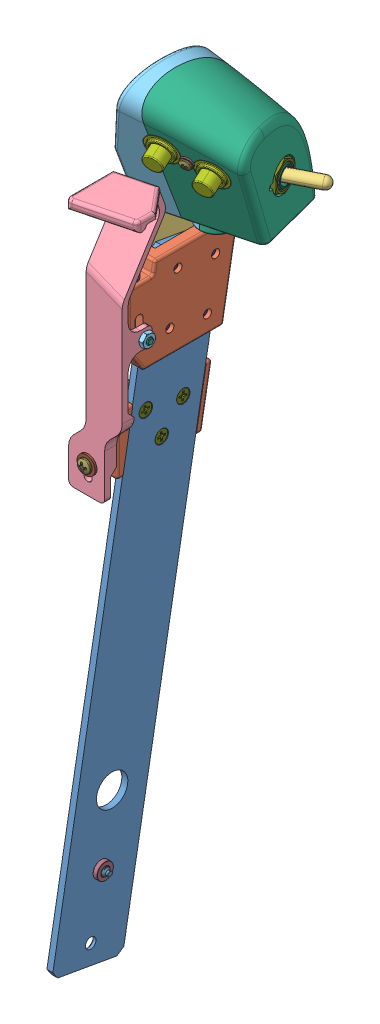
SolidWorks assembly Outboard Throttle Arm, configuration Default. Lengths in mm.
Overall size (82.55 408.55 128.06).
56 component instances, 35 part files, 59 mates.
Components (placement in the parent):
- Throttle Arm LH-1: Throttle Arm LH [Default] at (7.9447 45.466 -95.9039) x (0 0.984808 -0.173648) z (-1 0 0) size (312.92 38.1 3.17)
- LH Upper Adapter-1: LH Upper Adapter [Default] at (46.6096 413.27 112.6698) x (1 0 0) z (0 0.866025 -0.5) size (19.05 83.25 111.93)
- LH Grip Adapter-1: LH Grip Adapter [Default] at (1.3214 0.096 -0.0398) size (3.17 100.05 48.62)
- LH Finger Lift2-1: LH Finger Lift2 [Default] at (35.8375 39.1173 -95.0721) size (40.05 141.7 33.8)
- Outboard Throttle Grip-1: Outboard Throttle Grip [Default] at (-3.1678 298.9092 -120.6666) x (1 0 0) z (0 1 0) size (73.43 74.91 87.55)
  - Right Outboard Throttle Grip Housing-1: Right Outboard Throttle Grip Housing [Default] at origin size (26.95 74.91 87.55)
  - Left Outboard Throttle Grip Housing-1: Left Outboard Throttle Grip Housing [Default] at origin size (43.51 72.27 85.49)
  - P3-11122-1: P3-11122 [Default] at (22.2251 5.9653 48.09) x (-0.945358 -0.295929 0.136837) z (0.225703 -0.291136 0.929676) size (15.82 34.01 15.82)
  - P3-11122-2: P3-11122 [Default] at (41.7267 12.9829 42.839) x (-0.945358 -0.295929 0.136837) z (0.225703 -0.291136 0.929676) size (15.82 34.01 15.82)
  - 93365A140 - INSERT, 8-32, BRASS, FOR PLASTICS-1: 93365A140 - INSERT, 8-32, BRASS, FOR PLASTICS [93365A140] at (9.525 28.702 22.098) x (0 1 0) z (0 0 1) size (6.35 5.19 6.35)
  - 93365A140 - INSERT, 8-32, BRASS, FOR PLASTICS-2: 93365A140 - INSERT, 8-32, BRASS, FOR PLASTICS [93365A140] at (9.525 9.652 9.398) x (0 1 0) z (0 0 1) size (6.35 5.19 6.35)
  - 93365A140 - INSERT, 8-32, BRASS, FOR PLASTICS-3: 93365A140 - INSERT, 8-32, BRASS, FOR PLASTICS [93365A140] at (23.198 36.6475 6.35) x (0 1 0) z (0 0 1) size (6.35 5.19 6.35)
  - 93365A140 - INSERT, 8-32, BRASS, FOR PLASTICS-4: 93365A140 - INSERT, 8-32, BRASS, FOR PLASTICS [93365A140] at (23.198 6.35 25.4) x (0 1 0) z (0 0 1) size (6.35 5.19 6.35)
  - 93365A140 - INSERT, 8-32, BRASS, FOR PLASTICS-5: 93365A140 - INSERT, 8-32, BRASS, FOR PLASTICS [93365A140] at (23.198 17.5975 57.15) x (0 1 0) z (0 0 1) size (6.35 5.19 6.35)
  - 98381A471 - PIN, DOWEL, .125 X .500, ALLOY STEEL-1: 98381A471 - PIN, DOWEL, .125 X .500, ALLOY STEEL [98381A471] at (23.198 -10.9775 63.5) size (12.7 3.17 3.17)
  - 91249A197 - PHS, 8-32 x .750, 18-8, BLACK-OXIDE-1: 91249A197 - PHS, 8-32 x .750, 18-8, BLACK-OXIDE [91249A197] at (34.036 36.6475 6.35) x (0 0.936287 0.351235) z (-1 0 0) size (8.18 8.18 22.03)
  - 91249A197 - PHS, 8-32 x .750, 18-8, BLACK-OXIDE-3: 91249A197 - PHS, 8-32 x .750, 18-8, BLACK-OXIDE [91249A197] at (34.036 6.35 25.4) x (0 0.868755 0.495243) z (-1 0 0) size (8.18 8.18 22.03)
  - 91249A197 - PHS, 8-32 x .750, 18-8, BLACK-OXIDE-5: 91249A197 - PHS, 8-32 x .750, 18-8, BLACK-OXIDE [91249A197] at (34.036 17.5975 57.15) x (0 0.798623 0.601832) z (-1 0 0) size (8.18 8.18 22.03)
  - 93365A120_BRASS HEAT-SET INSERT FOR PLASTICS_4-40-1: 93365A120_BRASS HEAT-SET INSERT FOR PLASTICS_4-40 [93365A120] at (36.8165 -9.2433 38.4278) x (-0.683112 -0.40511 0.607655) z (0.691377 -0.090669 0.716783) size (4.37 3.82 4.37)
  - 90272A106 - PHS, 4-40 x .250, STEEL, ZINC-1: 90272A106 - PHS, 4-40 x .250, STEEL, ZINC [90272A106] at (35.4898 -4.1134 40.3564) x (-0.207842 -0.390854 0.89668) z (0.23528 -0.909761 -0.34202) size (5.56 5.56 8.42)
  - 90618A200 - WASHER, #4 X .250, 18-8, BLACK OXIDE, MS15795-803B-1: 90618A200 - WASHER, #4 X .250, 18-8, BLACK OXIDE, MS15795-803B [90618A200] at (36.9839 -9.8904 38.1845) x (0.971541 0.210217 0.109166) z (-0.027416 -0.357971 0.93333) size (6.35 0.71 6.35)
  - M2011B2B1W01-1: M2011B2B1W01 [Default] at (44.9176 20.4163 25.4) x (0 0 1) z (-0.25038 0.968148 0) size (18.21 44.24 19.49)
    - _M20112B2B1W01_switch_2-1: _M20112B2B1W01_switch_2 [Default] at origin size (7.9 9.17 13)
    - _M201B1M201_bushing_4-1: _M201B1M201_bushing_4 [Default] at (0 -0.254 0) size (12 19.04 13)
    - _AT503M_6-1: _AT503M_6 [Default] at (0 10.5308 0) x (1 0 0) z (0 1 0) size (16.01 15.91 2.39)
    - _AT506M_8-1: _AT506M_8 [Default] at (0 5.1714 0) x (0 0 1) z (0 1 0) size (18.62 18.21 2.79)
    - _AT508_10-1: _AT508_10 [Default] at (0 4.9174 0) x (1 0 0) z (0 -1 0) size (15.8 15.8 0.51)
    - _AT527M_12-1: _AT527M_12 [Default] at (0 3.6601 0) x (0.993403 0 -0.114675) z (0 -1 0) size (16.01 17.77 2.01)
    - _M201101_terminals_14-1: _M201101_terminals_14 [Default] at (0 -9.4234 0) size (6.38 5 12.5)
    - _M20B2_toggles_16-1: _M20B2_toggles_16 [Default] at (0 11.9888 0) x (0 0 -1) z (1 0 0) size (11.39 26.26 5.99)
- 90471A435 - FHS, 100 CSK, 8-32 x .625, STEEL, ZINC-1: 90471A435 - FHS, 100 CSK, 8-32 x .625, STEEL, ZINC [90471A435] at (5.2241 321.0072 -149.3686) x (0 -0.883365 0.468686) z (-1 0 0) size (7.92 7.92 15.88)
- 90471A435 - FHS, 100 CSK, 8-32 x .625, STEEL, ZINC-2: 90471A435 - FHS, 100 CSK, 8-32 x .625, STEEL, ZINC [90471A435] at (5.2241 308.3072 -130.3186) x (0 -0.788558 0.614961) z (-1 0 0) size (7.92 7.92 15.88)
- 90760A007 - NUT, 6-32, JAM, STEEL, ZINC-PLATED-4: 90760A007 - NUT, 6-32, JAM, STEEL, ZINC-PLATED [90760A007] at (20.0319 252.9228 -103.9621) x (0 0.3315 -0.943455) z (0 0.943455 0.3315) size (6.35 2.99 7.33)
- 91249A156 - PHS, 6-32 X .8750, 18-8, BLACK-OXIDE-1: 91249A156 - PHS, 6-32 X .8750, 18-8, BLACK-OXIDE [91249A156] at (22.0163 252.9228 -103.9621) x (0 -0.984808 0.173648) z (-1 0 0) size (6.86 6.86 24.73)
- 9657K298 - SPRING, COMPRESSION, .24 OD X .20 ID X 1.0 LG X .22 LG COMPRESSED, 2.7LBS-IN RATE, STEEL-1: 9657K298 - SPRING, COMPRESSION, .24 OD X .20 ID X 1.0 LG X .22 LG COMPRESSED, 2.7LBS-IN RATE, STEEL [9657K298] at (9.4607 268.8042 -103.9621) x (-0.985426 0 -0.170105) z (0 1 0) size (6.68 6.68 13.97)
- 91251A535 - SHCS, .25-20 X .375, STEEL, BLACK OXIDE-1: 91251A535 - SHCS, .25-20 X .375, STEEL, BLACK OXIDE [91251A535] at (9.4607 266.6452 -103.9621) x (0.994874 0 -0.101118) z (0 -1 0) size (9.53 9.53 16.56)
- 93365A160 - INSERT, .25-20, BRASS, FOR PLASTICS-1: 93365A160 - INSERT, .25-20, BRASS, FOR PLASTICS [93365A160] at (9.4607 276.1702 -103.9621) x (0.982082 0 -0.188455) z (0.188455 0 0.982082) size (9.53 8.41 9.53)
- 93365A130 - INSERT, 6-32, BRASS, FOR PLASTICS-1: 93365A130 - INSERT, 6-32, BRASS, FOR PLASTICS [93365A130] at (0.7438 192.3502 -98.2692) x (-0.85131 -0.524663 0) z (-0.524663 0.85131 0) size (5.56 4.29 5.56)
- 96765A115 - WASHER, #6, 18-8, BLACK-OXIDE-1: 96765A115 - WASHER, #6, 18-8, BLACK-OXIDE [96765A115] at (0.7438 192.3502 -90.9065) x (0.96896 0.247216 0) z (-0.247216 0.96896 0) size (9.53 0.99 9.53)
- 91249A148 - PHS, 6-32 X .500, 18-8, BLACK-OXIDE-1: 91249A148 - PHS, 6-32 X .500, 18-8, BLACK-OXIDE [91249A148] at (0.7438 192.3502 -103.6065) x (0.987351 0.158553 0) z (0 0 1) size (6.86 6.86 15.21)
- 95185A191 - NUT, PRESS-IN, 10-32 X .09 MIN PANEL THK, PEM-STYLE, .25 INSTALL HOLE, STEEL-1: 95185A191 - NUT, PRESS-IN, 10-32 X .09 MIN PANEL THK, PEM-STYLE, .25 INSTALL HOLE, STEEL [95185A191] at (11.8182 12.3223 -90.0598) x (0 0.536538 0.843876) z (1 0 0) size (8.64 8.64 5.12)
- 94115A827 - SCREW, SET, 10-32 X .375, NYLON-TIP, STEEL, BLACK OXIDE-1: 94115A827 - SCREW, SET, 10-32 X .375, NYLON-TIP, STEEL, BLACK OXIDE [94115A827] at (8.9369 12.3223 -90.0598) x (0 -0.536538 -0.843876) z (-1 0 0) size (4.92 4.93 11.07)
- 93365A130_BRASS HEAT-SET INSERT FOR PLASTICS_6-32-1: 93365A130_BRASS HEAT-SET INSERT FOR PLASTICS_6-32 [93365A130] at (6.3572 207.0599 -133.5273) x (0 -0.938399 0.345554) z (0 0.345554 0.938399) size (5.56 4.29 5.56)
- 90471A210 - FHS, 100DEG, 6-32 X .3125, STEEL, ZINC-PLATED-1: 90471A210 - FHS, 100DEG, 6-32 X .3125, STEEL, ZINC-PLATED [90471A210] at (7.827 207.0599 -133.5273) x (0 -0.991218 0.132234) z (1 0 0) size (6.65 6.65 8.22)
- 93365A130_BRASS HEAT-SET INSERT FOR PLASTICS_6-32-2: 93365A130_BRASS HEAT-SET INSERT FOR PLASTICS_6-32 [93365A130] at (6.3572 194.2381 -122.1364) x (0 -0.981317 0.192397) z (0 0.192397 0.981317) size (5.56 4.29 5.56)
- 90471A210 - FHS, 100DEG, 6-32 X .3125, STEEL, ZINC-PLATED-2: 90471A210 - FHS, 100DEG, 6-32 X .3125, STEEL, ZINC-PLATED [90471A210] at (7.827 194.2381 -122.1364) x (0 -0.999646 -0.026599) z (1 0 0) size (6.65 6.65 8.22)
- 93365A130_BRASS HEAT-SET INSERT FOR PLASTICS_6-32-4: 93365A130_BRASS HEAT-SET INSERT FOR PLASTICS_6-32 [93365A130] at (6.3572 210.5563 -113.6979) x (0 -0.997828 0.065878) z (0 0.065878 0.997828) size (5.56 4.29 5.56)
- 90471A210 - FHS, 100DEG, 6-32 X .3125, STEEL, ZINC-PLATED-4: 90471A210 - FHS, 100DEG, 6-32 X .3125, STEEL, ZINC-PLATED [90471A210] at (7.827 210.5563 -113.6979) x (0 -0.988122 -0.153669) z (1 0 0) size (6.65 6.65 8.22)
- 93365A130_BRASS HEAT-SET INSERT FOR PLASTICS_6-32-6: 93365A130_BRASS HEAT-SET INSERT FOR PLASTICS_6-32 [93365A130] at (9.837 244.4202 -140.115) x (0 -0.677696 0.735342) z (0 -0.735342 -0.677696) size (5.56 4.29 5.56)
- 93085A147 - FHS, 100 DEG, 6-32 x .4375, 18-8-1: 93085A147 - FHS, 100 DEG, 6-32 x .4375, 18-8 [93085A147] at (4.7062 244.4202 -140.115) x (0 -0.380204 0.924902) z (-1 0 0) size (7.09 7.09 11.41)
- 93365A130_BRASS HEAT-SET INSERT FOR PLASTICS_6-32-7: 93365A130_BRASS HEAT-SET INSERT FOR PLASTICS_6-32 [93365A130] at (9.837 269.8202 -144.525) x (0 -0.785714 0.61859) z (0 -0.61859 -0.785714) size (5.56 4.29 5.56)
- 93085A147 - FHS, 100 DEG, 6-32 x .4375, 18-8-2: 93085A147 - FHS, 100 DEG, 6-32 x .4375, 18-8 [93085A147] at (4.7062 269.8202 -144.525) x (0 -0.522041 0.85292) z (-1 0 0) size (7.09 7.09 11.41)
- 93365A130_BRASS HEAT-SET INSERT FOR PLASTICS_6-32-9: 93365A130_BRASS HEAT-SET INSERT FOR PLASTICS_6-32 [93365A130] at (9.837 273.2354 -124.5439) x (0 -0.858085 0.513508) z (0 -0.513508 -0.858085) size (5.56 4.29 5.56)
- 93085A147 - FHS, 100 DEG, 6-32 x .4375, 18-8-4: 93085A147 - FHS, 100 DEG, 6-32 x .4375, 18-8 [93085A147] at (4.7062 273.2354 -124.5439) x (0 -0.626396 0.779505) z (-1 0 0) size (7.09 7.09 11.41)
- 93365A130_BRASS HEAT-SET INSERT FOR PLASTICS_6-32-11: 93365A130_BRASS HEAT-SET INSERT FOR PLASTICS_6-32 [93365A130] at (9.837 247.8126 -120.2672) x (0 -0.902214 0.431288) z (0 -0.431288 -0.902214) size (5.56 4.29 5.56)
- 93085A147 - FHS, 100 DEG, 6-32 x .4375, 18-8-6: 93085A147 - FHS, 100 DEG, 6-32 x .4375, 18-8 [93085A147] at (4.7062 247.8126 -120.2672) x (0 -0.696328 0.717724) z (-1 0 0) size (7.09 7.09 11.41)
Mates (geometry in assembly coordinates):
- Coincident50: coincident anti-aligned: plane of Throttle Arm LH-1 through (6.3572 45.466 -95.9039) normal (-1 0 0); plane of LH Upper Adapter-1 through (6.3572 204.0324 2.462) normal (1 0 0)
- Coincident52: coincident aligned: plane of LH Upper Adapter-1 through (15.6663 235.1354 -148.6916) normal (0 -0.173648 -0.984808); plane of Throttle Arm LH-1 through (6.3572 42.158 -114.6645) normal (0 -0.173648 -0.984808)
- Concentric21: concentric aligned: cylinder of Throttle Arm LH-1 through (6.3572 273.2354 -124.5439) axis (-1 0 0) radius 2.1526; cylinder of LH Grip Adapter-1 through (3.1822 273.2354 -124.5439) axis (-1 0 0) radius 2.1526
- Concentric22: concentric aligned: cylinder of Throttle Arm LH-1 through (6.3572 244.4202 -140.115) axis (-1 0 0) radius 2.1526; cylinder of LH Grip Adapter-1 through (3.1822 244.4202 -140.115) axis (-1 0 0) radius 2.1526
- Coincident56: coincident anti-aligned: plane of Throttle Arm LH-1 through (6.3572 45.466 -95.9039) normal (-1 0 0); plane of LH Grip Adapter-1 through (6.3572 0.096 -0.0398) normal (1 0 0)
- Concentric229: concentric anti-aligned: cone of LH Upper Adapter-1 through (9.4607 276.1702 -103.9621) axis (0 -1 0); cylinder of 93365A160 - INSERT, .25-20, BRASS, FOR PLASTICS-1 through (9.4607 276.1702 -103.9621) axis (0 1 0) radius 4.4323
- Coincident299: coincident aligned: plane of LH Upper Adapter-1 through (15.6663 276.1702 112.6698) normal (0 1 0); plane of 93365A160 - INSERT, .25-20, BRASS, FOR PLASTICS-1 through (9.4607 276.1702 -103.9621) normal (0 1 0)
- Concentric230: concentric aligned: cone of LH Upper Adapter-1 through (9.4607 276.1702 -103.9621) axis (0 -1 0); line of 9657K298 - SPRING, COMPRESSION, .24 OD X .20 ID X 1.0 LG X .22 LG COMPRESSED, 2.7LBS-IN RATE, STEEL-1 through (9.4607 268.8042 -103.9621) axis (0 -1 0)
- Concentric234: concentric anti-aligned: cone of LH Upper Adapter-1 through (0.7438 192.3502 -98.2692) axis (0 0 -1); cylinder of 93365A130 - INSERT, 6-32, BRASS, FOR PLASTICS-1 through (0.7438 192.3502 -98.2692) axis (0 0 1) radius 2.5273
- Coincident302: coincident aligned: plane of LH Upper Adapter-1 through (15.6663 413.27 -98.2692) normal (0 0 1); plane of 93365A130 - INSERT, 6-32, BRASS, FOR PLASTICS-1 through (0.7438 192.3502 -98.2692) normal (0 0 1)
- Coincident249: coincident anti-aligned: plane of LH Grip Adapter-1 through (3.1822 330.6592 -159.3544) normal (0 1 0); plane of Outboard Throttle Grip-1/Right Outboard Throttle Grip Housing-1 through (3.1822 330.6592 -142.2314) normal (0 -1 0)
- Coincident250: coincident anti-aligned: plane of LH Grip Adapter-1 through (3.1822 330.6592 -120.6666) normal (0 0 1); plane of Outboard Throttle Grip-1/Right Outboard Throttle Grip Housing-1 through (0.0072 298.9092 -120.6666) normal (0 0 -1)
- Coincident251: coincident anti-aligned: plane of LH Grip Adapter-1 through (6.3572 0.096 -0.0398) normal (1 0 0); plane of Outboard Throttle Grip-1/Right Outboard Throttle Grip Housing-1 through (6.3572 298.9092 -120.6666) normal (-1 0 0)
- Concentric223: concentric aligned: cone of LH Grip Adapter-1 through (3.1822 321.0072 -149.3686) axis (1 0 0); cone of 90471A435 - FHS, 100 CSK, 8-32 x .625, STEEL, ZINC-1 through (3.3953 321.0072 -149.3686) axis (1 0 0)
- Coincident294: coincident aligned: cone of LH Grip Adapter-1 through (3.1822 321.0072 -149.3686) axis (1 0 0); cone of 90471A435 - FHS, 100 CSK, 8-32 x .625, STEEL, ZINC-1 through (3.3953 321.0072 -149.3686) axis (1 0 0)
- Concentric224: concentric aligned: cone of LH Grip Adapter-1 through (3.1822 308.3072 -130.3186) axis (1 0 0); cone of 90471A435 - FHS, 100 CSK, 8-32 x .625, STEEL, ZINC-2 through (3.3953 308.3072 -130.3186) axis (1 0 0)
- Coincident295: coincident aligned: cone of LH Grip Adapter-1 through (3.1822 308.3072 -130.3186) axis (1 0 0); cone of 90471A435 - FHS, 100 CSK, 8-32 x .625, STEEL, ZINC-2 through (3.3953 308.3072 -130.3186) axis (1 0 0)
- Concentric225: concentric anti-aligned: circle of 90760A007 - NUT, 6-32, JAM, STEEL, ZINC-PLATED-4; cylinder of 91249A156 - PHS, 6-32 X .8750, 18-8, BLACK-OXIDE-1 through (22.0163 252.9228 -103.9621) axis (1 0 0) radius 3.429
- Tangent6: tangent: circle of 9657K298 - SPRING, COMPRESSION, .24 OD X .20 ID X 1.0 LG X .22 LG COMPRESSED, 2.7LBS-IN RATE, STEEL-1; plane of 93365A160 - INSERT, .25-20, BRASS, FOR PLASTICS-1 through (9.4607 268.5502 -103.9621) normal (0 -1 0)
- Concentric228: concentric anti-aligned: cylinder of 91251A535 - SHCS, .25-20 X .375, STEEL, BLACK OXIDE-1 through (9.4607 282.5202 -103.9621) axis (0 -1 0) radius 4.7625; cylinder of 93365A160 - INSERT, .25-20, BRASS, FOR PLASTICS-1 through (9.4607 276.1702 -103.9621) axis (0 1 0) radius 4.4323
- Coincident298: coincident anti-aligned: plane of 91251A535 - SHCS, .25-20 X .375, STEEL, BLACK OXIDE-1 through (9.4607 276.1702 -103.9621) normal (0 -1 0); plane of 93365A160 - INSERT, .25-20, BRASS, FOR PLASTICS-1 through (9.4607 276.1702 -103.9621) normal (0 1 0)
- Concentric232: concentric anti-aligned: circle of 93365A130 - INSERT, 6-32, BRASS, FOR PLASTICS-1; cylinder of 96765A115 - WASHER, #6, 18-8, BLACK-OXIDE-1 through (0.7438 192.3502 -91.8971) axis (0 0 1) radius 4.7625
- Concentric233: concentric anti-aligned: cylinder of 96765A115 - WASHER, #6, 18-8, BLACK-OXIDE-1 through (0.7438 192.3502 -91.8971) axis (0 0 1) radius 4.7625; cylinder of 91249A148 - PHS, 6-32 X .500, 18-8, BLACK-OXIDE-1 through (0.7438 192.3502 -103.6065) axis (0 0 -1) radius 3.429
- Coincident301: coincident anti-aligned: plane of 96765A115 - WASHER, #6, 18-8, BLACK-OXIDE-1 through (0.7438 192.3502 -90.9065) normal (0 0 1); plane of 91249A148 - PHS, 6-32 X .500, 18-8, BLACK-OXIDE-1 through (0.7438 192.3502 -90.9065) normal (0 0 -1)
- Distance1: distance = 2.4765 mm aligned: plane of 94115A827 - SCREW, SET, 10-32 X .375, NYLON-TIP, STEEL, BLACK OXIDE-1 through (14.2947 11.3176 -89.4209) normal (1 0 0); plane of 95185A191 - NUT, PRESS-IN, 10-32 X .09 MIN PANEL THK, PEM-STYLE, .25 INSTALL HOLE, STEEL-1 through (11.8182 12.3223 -90.0598) normal (1 0 0)
- Concentric243: concentric aligned: cylinder of 95185A191 - NUT, PRESS-IN, 10-32 X .09 MIN PANEL THK, PEM-STYLE, .25 INSTALL HOLE, STEEL-1 through (9.5322 12.3223 -90.0598) axis (1 0 0) radius 4.318; cylinder of 94115A827 - SCREW, SET, 10-32 X .375, NYLON-TIP, STEEL, BLACK OXIDE-1 through (14.2947 12.3223 -90.0598) axis (1 0 0) radius 1.1906
- Concentric244: concentric anti-aligned: cylinder of Throttle Arm LH-1 through (6.3572 12.3223 -90.0598) axis (-1 0 0) radius 3.175; cylinder of 95185A191 - NUT, PRESS-IN, 10-32 X .09 MIN PANEL THK, PEM-STYLE, .25 INSTALL HOLE, STEEL-1 through (9.5322 12.3223 -90.0598) axis (1 0 0) radius 4.318
- Coincident312: coincident anti-aligned: plane of Throttle Arm LH-1 through (9.5322 45.466 -95.9039) normal (1 0 0); plane of 95185A191 - NUT, PRESS-IN, 10-32 X .09 MIN PANEL THK, PEM-STYLE, .25 INSTALL HOLE, STEEL-1 through (9.5322 12.3223 -90.0598) normal (-1 0 0)
- Concentric245: concentric anti-aligned: cone of LH Upper Adapter-1 through (6.3572 207.0599 -133.5273) axis (-1 0 0); cylinder of 93365A130_BRASS HEAT-SET INSERT FOR PLASTICS_6-32-1 through (6.3572 207.0599 -133.5273) axis (1 0 0) radius 2.5273
- Coincident313: coincident aligned: plane of LH Upper Adapter-1 through (6.3572 204.0324 2.462) normal (1 0 0); plane of 93365A130_BRASS HEAT-SET INSERT FOR PLASTICS_6-32-1 through (6.3572 207.0599 -133.5273) normal (1 0 0)
- Concentric246: concentric aligned: cone of Throttle Arm LH-1 through (9.5322 207.0599 -133.5273) axis (-1 0 0); cone of 90471A210 - FHS, 100DEG, 6-32 X .3125, STEEL, ZINC-PLATED-1 through (9.351 207.0599 -133.5273) axis (-1 0 0)
- Coincident314: coincident aligned: cone of Throttle Arm LH-1 through (9.5322 207.0599 -133.5273) axis (-1 0 0); cone of 90471A210 - FHS, 100DEG, 6-32 X .3125, STEEL, ZINC-PLATED-1 through (9.351 207.0599 -133.5273) axis (-1 0 0)
- Concentric247: concentric anti-aligned: cone of LH Upper Adapter-1 through (6.3572 194.2381 -122.1364) axis (-1 0 0); cylinder of 93365A130_BRASS HEAT-SET INSERT FOR PLASTICS_6-32-2 through (6.3572 194.2381 -122.1364) axis (1 0 0) radius 2.5273
- Coincident315: coincident aligned: plane of LH Upper Adapter-1 through (6.3572 204.0324 2.462) normal (1 0 0); plane of 93365A130_BRASS HEAT-SET INSERT FOR PLASTICS_6-32-2 through (6.3572 194.2381 -122.1364) normal (1 0 0)
- Concentric248: concentric aligned: cone of Throttle Arm LH-1 through (9.5322 194.2381 -122.1364) axis (-1 0 0); cone of 90471A210 - FHS, 100DEG, 6-32 X .3125, STEEL, ZINC-PLATED-2 through (9.351 194.2381 -122.1364) axis (-1 0 0)
- Coincident316: coincident aligned: cone of Throttle Arm LH-1 through (9.5322 194.2381 -122.1364) axis (-1 0 0); cone of 90471A210 - FHS, 100DEG, 6-32 X .3125, STEEL, ZINC-PLATED-2 through (9.351 194.2381 -122.1364) axis (-1 0 0)
- Concentric249: concentric anti-aligned: cone of LH Upper Adapter-1 through (6.3572 210.5563 -113.6979) axis (-1 0 0); cylinder of 93365A130_BRASS HEAT-SET INSERT FOR PLASTICS_6-32-4 through (6.3572 210.5563 -113.6979) axis (1 0 0) radius 2.5273
- Coincident317: coincident aligned: plane of LH Upper Adapter-1 through (6.3572 204.0324 2.462) normal (1 0 0); plane of 93365A130_BRASS HEAT-SET INSERT FOR PLASTICS_6-32-4 through (6.3572 210.5563 -113.6979) normal (1 0 0)
- Concentric250: concentric aligned: cone of Throttle Arm LH-1 through (9.5322 210.5563 -113.6979) axis (-1 0 0); cone of 90471A210 - FHS, 100DEG, 6-32 X .3125, STEEL, ZINC-PLATED-4 through (9.351 210.5563 -113.6979) axis (-1 0 0)
- Coincident318: coincident aligned: cone of Throttle Arm LH-1 through (9.5322 210.5563 -113.6979) axis (-1 0 0); cone of 90471A210 - FHS, 100DEG, 6-32 X .3125, STEEL, ZINC-PLATED-4 through (9.351 210.5563 -113.6979) axis (-1 0 0)
- Concentric251: concentric anti-aligned: cone of LH Upper Adapter-1 through (9.837 244.4202 -140.115) axis (1 0 0); cylinder of 93365A130_BRASS HEAT-SET INSERT FOR PLASTICS_6-32-6 through (9.837 244.4202 -140.115) axis (-1 0 0) radius 2.5273
- Coincident319: coincident aligned: plane of LH Upper Adapter-1 through (9.837 307.4311 -15.77) normal (-1 0 0); plane of 93365A130_BRASS HEAT-SET INSERT FOR PLASTICS_6-32-6 through (9.837 244.4202 -140.115) normal (-1 0 0)
- Concentric252: concentric aligned: cone of LH Grip Adapter-1 through (3.1822 244.4202 -140.115) axis (1 0 0); cone of 93085A147 - FHS, 100 DEG, 6-32 x .4375, 18-8-1 through (3.1822 244.4202 -140.115) axis (1 0 0)
- Coincident320: coincident aligned: cone of LH Grip Adapter-1 through (3.1822 244.4202 -140.115) axis (1 0 0); cone of 93085A147 - FHS, 100 DEG, 6-32 x .4375, 18-8-1 through (3.1822 244.4202 -140.115) axis (1 0 0)
- Concentric253: concentric anti-aligned: cone of LH Upper Adapter-1 through (9.837 269.8202 -144.525) axis (1 0 0); cylinder of 93365A130_BRASS HEAT-SET INSERT FOR PLASTICS_6-32-7 through (9.837 269.8202 -144.525) axis (-1 0 0) radius 2.5273
- Coincident321: coincident aligned: plane of LH Upper Adapter-1 through (9.837 307.4311 -15.77) normal (-1 0 0); plane of 93365A130_BRASS HEAT-SET INSERT FOR PLASTICS_6-32-7 through (9.837 269.8202 -144.525) normal (-1 0 0)
- Concentric254: concentric aligned: cone of LH Grip Adapter-1 through (3.1822 269.8202 -144.525) axis (1 0 0); cone of 93085A147 - FHS, 100 DEG, 6-32 x .4375, 18-8-2 through (3.1822 269.8202 -144.525) axis (1 0 0)
- Coincident322: coincident aligned: cone of LH Grip Adapter-1 through (3.1822 269.8202 -144.525) axis (1 0 0); cone of 93085A147 - FHS, 100 DEG, 6-32 x .4375, 18-8-2 through (3.1822 269.8202 -144.525) axis (1 0 0)
- Concentric255: concentric anti-aligned: cone of LH Upper Adapter-1 through (9.837 273.2354 -124.5439) axis (1 0 0); cylinder of 93365A130_BRASS HEAT-SET INSERT FOR PLASTICS_6-32-9 through (9.837 273.2354 -124.5439) axis (-1 0 0) radius 2.5273
- Coincident323: coincident aligned: plane of LH Upper Adapter-1 through (9.837 307.4311 -15.77) normal (-1 0 0); plane of 93365A130_BRASS HEAT-SET INSERT FOR PLASTICS_6-32-9 through (9.837 273.2354 -124.5439) normal (-1 0 0)
- Concentric256: concentric aligned: cone of LH Grip Adapter-1 through (3.1822 273.2354 -124.5439) axis (1 0 0); cone of 93085A147 - FHS, 100 DEG, 6-32 x .4375, 18-8-4 through (3.1822 273.2354 -124.5439) axis (1 0 0)
- Coincident324: coincident aligned: cone of LH Grip Adapter-1 through (3.1822 273.2354 -124.5439) axis (1 0 0); cone of 93085A147 - FHS, 100 DEG, 6-32 x .4375, 18-8-4 through (3.1822 273.2354 -124.5439) axis (1 0 0)
- Concentric257: concentric anti-aligned: cone of LH Upper Adapter-1 through (9.837 247.8126 -120.2672) axis (1 0 0); cylinder of 93365A130_BRASS HEAT-SET INSERT FOR PLASTICS_6-32-11 through (9.837 247.8126 -120.2672) axis (-1 0 0) radius 2.5273
- Coincident325: coincident aligned: plane of LH Upper Adapter-1 through (9.837 307.4311 -15.77) normal (-1 0 0); plane of 93365A130_BRASS HEAT-SET INSERT FOR PLASTICS_6-32-11 through (9.837 247.8126 -120.2672) normal (-1 0 0)
- Concentric258: concentric aligned: cone of LH Grip Adapter-1 through (3.1822 247.8126 -120.2672) axis (1 0 0); cone of 93085A147 - FHS, 100 DEG, 6-32 x .4375, 18-8-6 through (3.1822 247.8126 -120.2672) axis (1 0 0)
- Coincident326: coincident aligned: cone of LH Grip Adapter-1 through (3.1822 247.8126 -120.2672) axis (1 0 0); cone of 93085A147 - FHS, 100 DEG, 6-32 x .4375, 18-8-6 through (3.1822 247.8126 -120.2672) axis (1 0 0)
- Width13: width anti-aligned: plane of LH Finger Lift2-1 through (-0.2087 39.1173 -91.8971) normal (-1 0 0); plane of LH Finger Lift2-1 through (18.8413 39.1173 -91.8971) normal (1 0 0); plane of LH Upper Adapter-1 through (15.6663 413.27 112.6698) normal (1 0 0); plane of LH Upper Adapter-1 through (2.9663 413.27 112.6698) normal (-1 0 0)
- Concentric380: concentric anti-aligned: cylinder of LH Upper Adapter-1 through (15.6663 252.9228 -103.9621) axis (1 0 0) radius 2.1526; cylinder of LH Finger Lift2-1 through (-0.2087 252.9228 -103.9621) axis (-1 0 0) radius 2.1526
- Parallel1: parallel anti-aligned: plane of LH Upper Adapter-1 through (15.6663 413.27 -98.2692) normal (0 0 1); plane of LH Finger Lift2-1 through (0.7438 192.3502 -98.2471) normal (0 0 -1)
